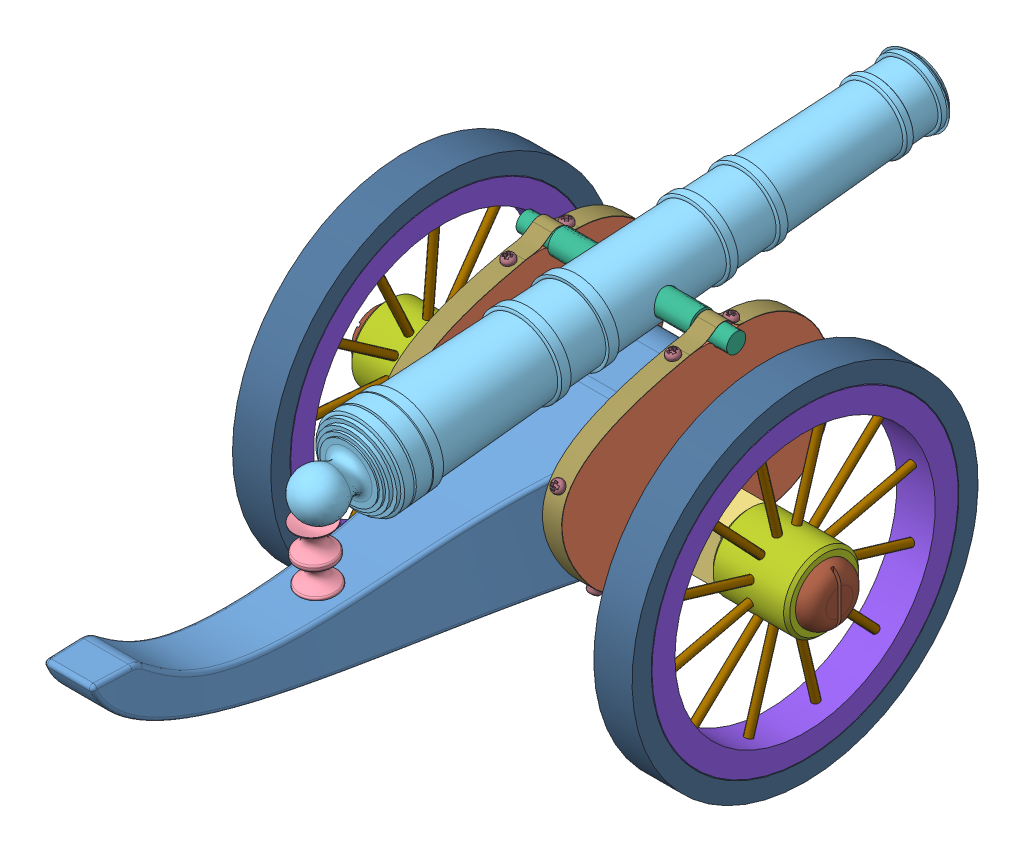
SolidWorks assembly ModelCannon, configuration Default. Lengths in mm.
Overall size (156.04 152.73 283.8).
65 component instances, 14 part files, 74 mates.
Components (placement in the parent):
- Body-1: Body [Default] at (64.8503 106.6025 167.4503) size (66.11 50.71 208.98)
- SideSupport-1: SideSupport [Default] at (37.5453 116.1275 93.9173) size (6.35 57.15 95.65)
- SideSupport-2: SideSupport [Default] at (92.1553 116.1275 93.9173) size (6.35 57.15 95.65)
- Axle-1: Axle [Default] at (64.8503 96.0615 93.7903) size (93.98 16.51 16.51)
- Bolster-1: Bolster [Default] at (64.8503 119.3352 189.7053) x (1 0 0) z (0 -0.083524 0.996506) size (12.7 31.75 12.7)
- Barrel-1: Barrel [Default] at (64.8503 144.7025 85.0053) x (1 0 0) z (0 0.086593 -0.996244) size (28.78 28.78 208.03)
- BarrelAxle-1: BarrelAxle [Default] at (64.8503 144.7025 85.0053) x (-1 0 0) z (0 0.924225 0.381849) size (69.85 8.13 8.13)
- Wheel-1: Wheel [Default] at (113.4219 81.2489 76.5414) x (1 0 0) z (0 0.203628 0.979048) size (25.4 129.14 129.14)
  - Hub-1: Hub [Default] at (11.6263 10.9898 19.9037) size (25.4 24.89 24.89)
  - InnerRim-1: InnerRim [Default] at (11.6263 10.9898 19.9037) x (1 0 0) z (0 -0.325508 0.945539) size (12.7 101.6 101.6)
  - Spoke-1: Spoke [Default] at (11.6263 -16.3912 7.1017) x (0.733186 -0.288022 0.616021) z (-0.680028 -0.310536 0.664175) size (2.54 40.64 2.54)
  - Spoke-2: Spoke [Default] at (11.6263 -19.1238 22.5073) x (0.45302 0.076792 0.888187) z (-0.8915 0.039022 0.451337) size (2.54 40.64 2.54)
  - Spoke-3: Spoke [Default] at (11.6263 -6.3218 -4.8737) x (-0.558086 -0.680204 0.47525) z (-0.829783 0.457484 -0.319638) size (2.54 40.64 2.54)
  - Spoke-4: Spoke [Default] at (11.6263 -13.7876 37.2153) x (1 0 0) z (0 0.572739 0.819737) size (2.54 40.64 2.54)
  - Spoke-5: Spoke [Default] at (11.6263 -1.8122 47.2847) x (0.999266 -0.0347 -0.016224) z (0.038306 0.905211 0.423233) size (2.54 40.64 2.54)
  - Spoke-6: Spoke [Default] at (11.6263 8.3862 -10.21) x (0.430926 -0.899033 0.07773) z (-0.902387 -0.429324 0.037119) size (2.54 40.64 2.54)
  - Spoke-7: Spoke [Default] at (11.6263 23.7918 -7.4773) x (1 0 0) z (0 0.905876 0.423544) size (2.54 40.64 2.54)
  - Spoke-8: Spoke [Default] at (11.6263 13.5934 50.0173) x (0.808821 -0.58587 0.050654) z (-0.588055 -0.805815 0.06967) size (2.54 40.64 2.54)
  - Spoke-9: Spoke [Default] at (11.6263 28.3014 44.6811) x (0.274974 0.788138 -0.550661) z (0.961452 -0.225406 0.157488) size (2.54 40.64 2.54)
  - Spoke-10: Spoke [Default] at (11.6263 41.1035 17.3001) x (0.021573 0.086118 0.996051) z (-0.999767 0.001858 0.021493) size (2.54 40.64 2.54)
  - Spoke-11: Spoke [Default] at (11.6263 35.7672 2.5921) x (0.597522 0.459253 0.657309) z (-0.801853 0.342224 0.489811) size (2.54 40.64 2.54)
  - Spoke-12: Spoke [Default] at (11.6263 38.3708 32.7057) x (0.995605 -0.039667 0.08484) z (-0.093656 -0.421682 0.901894) size (2.54 40.64 2.54)
  - OuterRim-1: OuterRim [Default] at (11.6263 10.9898 19.9037) size (12.7 114.81 114.81)
- Wheel-2: Wheel [Default] at (-6.4661 85.0716 73.8866) size (25.4 129.14 129.14)
  - Hub-1: Hub [Default] at (11.6263 10.9898 19.9037) size (25.4 24.89 24.89)
  - InnerRim-1: InnerRim [Default] at (11.6263 10.9898 19.9037) x (1 0 0) z (0 -0.325508 0.945539) size (12.7 101.6 101.6)
  - Spoke-1: Spoke [Default] at (11.6263 -16.3912 7.1017) x (0.733186 -0.288022 0.616021) z (-0.680028 -0.310536 0.664175) size (2.54 40.64 2.54)
  - Spoke-2: Spoke [Default] at (11.6263 -19.1238 22.5073) x (0.45302 0.076792 0.888187) z (-0.8915 0.039022 0.451337) size (2.54 40.64 2.54)
  - Spoke-3: Spoke [Default] at (11.6263 -6.3218 -4.8737) x (-0.558086 -0.680204 0.47525) z (-0.829783 0.457484 -0.319638) size (2.54 40.64 2.54)
  - Spoke-4: Spoke [Default] at (11.6263 -13.7876 37.2153) x (1 0 0) z (0 0.572739 0.819737) size (2.54 40.64 2.54)
  - Spoke-5: Spoke [Default] at (11.6263 -1.8122 47.2847) x (0.999266 -0.0347 -0.016224) z (0.038306 0.905211 0.423233) size (2.54 40.64 2.54)
  - Spoke-6: Spoke [Default] at (11.6263 8.3862 -10.21) x (0.430926 -0.899033 0.07773) z (-0.902387 -0.429324 0.037119) size (2.54 40.64 2.54)
  - Spoke-7: Spoke [Default] at (11.6263 23.7918 -7.4773) x (1 0 0) z (0 0.905876 0.423544) size (2.54 40.64 2.54)
  - Spoke-8: Spoke [Default] at (11.6263 13.5934 50.0173) x (0.808821 -0.58587 0.050654) z (-0.588055 -0.805815 0.06967) size (2.54 40.64 2.54)
  - Spoke-9: Spoke [Default] at (11.6263 28.3014 44.6811) x (0.274974 0.788138 -0.550661) z (0.961452 -0.225406 0.157488) size (2.54 40.64 2.54)
  - Spoke-10: Spoke [Default] at (11.6263 41.1035 17.3001) x (0.021573 0.086118 0.996051) z (-0.999767 0.001858 0.021493) size (2.54 40.64 2.54)
  - Spoke-11: Spoke [Default] at (11.6263 35.7672 2.5921) x (0.597522 0.459253 0.657309) z (-0.801853 0.342224 0.489811) size (2.54 40.64 2.54)
  - Spoke-12: Spoke [Default] at (11.6263 38.3708 32.7057) x (0.995605 -0.039667 0.08484) z (-0.093656 -0.421682 0.901894) size (2.54 40.64 2.54)
  - OuterRim-1: OuterRim [Default] at (11.6263 10.9898 19.9037) size (12.7 114.81 114.81)
- WheelScrew-1: WheelScrew [Default] at (124.7943 96.0615 93.7903) x (0 -1 0) z (0 0 1) size (19.05 49.06 19.05)
- WheelScrew-2: WheelScrew [Default] at (5.4143 96.0615 93.7903) x (0 -0.701868 -0.712307) z (0 0.712307 -0.701868) size (19.05 49.06 19.05)
- CopperStrip-1: CopperStrip [Default] at (37.5453 116.1275 93.9173) size (6.35 61.09 89.18)
- CopperStrip-2: CopperStrip [Default] at (92.1553 116.1275 93.9173) size (6.35 61.09 89.18)
- SmallScrew-2: SmallScrew [Default] at (92.1553 140.8063 97.588) x (-0.302476 -0.207362 0.930327) z (0.953157 -0.065804 0.295232) size (4.06 8.22 4.06)
- SmallScrew-3: SmallScrew [Default] at (37.5453 97.6029 56.9597) x (1 0 0) z (0 -0.770151 0.637861) size (4.06 8.22 4.06)
- SmallScrew-4: SmallScrew [Default] at (37.5453 118.2993 69.4106) x (1 0 0) z (0 -0.969773 -0.244009) size (4.06 8.22 4.06)
- SmallScrew-5: SmallScrew [Default] at (92.1553 123.601 133.4113) x (1 0 0) z (0 0.862464 -0.506118) size (4.06 8.22 4.06)
- SmallScrew-6: SmallScrew [Default] at (92.1553 92.9297 122.4523) x (1 0 0) z (0 0.51955 0.85444) size (4.06 8.22 4.06)
- SmallScrew-7: SmallScrew [Default] at (92.1553 97.6029 56.9597) x (0.807604 0.454178 -0.376163) z (0.589725 -0.621977 0.515139) size (4.06 8.22 4.06)
- SmallScrew-8: SmallScrew [Default] at (92.1553 141.6545 79.1094) x (0.084554 0 0.996419) z (0.996419 0 -0.084554) size (4.06 8.22 4.06)
- SmallScrew-9: SmallScrew [Default] at (92.1553 90.6005 82.9953) x (-0.417971 0 -0.90846) z (0.90846 0 -0.417971) size (4.06 8.22 4.06)
- SmallScrew-10: SmallScrew [Default] at (92.1553 122.3563 53.2869) x (-0.522268 0.827004 0.208086) z (0.852781 0.506482 0.127438) size (4.06 8.22 4.06)
- SmallScrew-11: SmallScrew [Default] at (37.5453 90.6005 104.8393) size (4.06 8.22 4.06)
- SmallScrew-12: SmallScrew [Default] at (37.5453 90.6005 82.9953) size (4.06 8.22 4.06)
- SmallScrew-13: SmallScrew [Default] at (92.1553 90.6005 104.8393) x (0.096077 0 0.995374) z (-0.995374 0 0.096077) size (4.06 8.22 4.06)
- SmallScrew-14: SmallScrew [Default] at (37.5453 141.6545 79.1094) x (-0.68281 0 0.730596) z (0.730596 0 0.68281) size (4.06 8.22 4.06)
- SmallScrew-15: SmallScrew [Default] at (37.5453 123.601 133.4113) x (0.9252 0.327288 -0.192062) z (-0.379481 0.797951 -0.468261) size (4.06 8.22 4.06)
- SmallScrew-16: SmallScrew [Default] at (37.5453 140.8063 97.588) x (0.878793 0.103817 -0.465773) z (-0.477202 0.191184 -0.857745) size (4.06 8.22 4.06)
- SmallScrew-17: SmallScrew [Default] at (37.5453 92.9297 122.4523) x (1 0 0) z (0 0.51955 0.85444) size (4.06 8.22 4.06)
- SmallScrew-19: SmallScrew [Default] at (37.5453 122.3563 53.2869) x (0.909668 -0.402781 -0.101346) z (-0.415335 -0.882172 -0.221967) size (4.06 8.22 4.06)
- BigScrew-1: BigScrew [Default] at (85.8053 107.4915 82.3603) x (0 0.752048 0.659108) z (0 0.659108 -0.752048) size (6.35 21.7 6.35)
- BigScrew-2: BigScrew [Default] at (85.8053 107.4915 105.4743) x (0 -0.455233 0.890372) z (0 0.890372 0.455233) size (6.35 21.7 6.35)
- BigScrew-3: BigScrew [Default] at (43.8953 107.4915 105.4743) x (0 0.044529 -0.999008) z (0 0.999008 0.044529) size (6.35 21.7 6.35)
- BigScrew-4: BigScrew [Default] at (43.8953 107.4915 82.3603) x (0 -0.996116 -0.088054) z (0 0.088054 -0.996116) size (6.35 21.7 6.35)
- BigScrew-5: BigScrew [Default] at (64.8503 97.3315 93.7903) x (-0.837169 0 -0.546944) z (-0.546944 0 0.837169) size (6.35 21.7 6.35)
Mates (geometry in assembly coordinates):
- Coincident1: coincident aligned: circle of Body-1; cylinder of SideSupport-2 through (88.9803 107.4915 82.3603) axis (1 0 0) radius 1.27
- Concentric1: concentric aligned: cylinder of Body-1 through (82.6303 107.4915 105.4743) axis (1 0 0) radius 1.27; cylinder of SideSupport-2 through (88.9803 107.4915 105.4743) axis (1 0 0) radius 1.27
- Coincident2: coincident anti-aligned: plane of Body-1 through (88.9803 96.6338 221.3715) normal (1 0 0); plane of SideSupport-2 through (88.9803 116.1275 93.9173) normal (-1 0 0)
- Concentric2: concentric anti-aligned: cylinder of Body-1 through (47.0703 107.4915 82.3603) axis (-1 0 0) radius 1.27; cylinder of SideSupport-1 through (34.3703 107.4915 82.3603) axis (1 0 0) radius 1.27
- Concentric3: concentric anti-aligned: cylinder of Body-1 through (47.0703 107.4915 105.4743) axis (-1 0 0) radius 1.27; cylinder of SideSupport-1 through (34.3703 107.4915 105.4743) axis (1 0 0) radius 1.27
- Coincident3: coincident anti-aligned: plane of Body-1 through (40.7203 96.6338 221.3715) normal (-1 0 0); plane of SideSupport-1 through (40.7203 116.1275 93.9173) normal (1 0 0)
- Concentric4: concentric anti-aligned: cylinder of Body-1 through (64.8503 104.3165 93.7903) axis (0 -1 0) radius 1.2637; cylinder of Axle-1 through (64.8503 87.8065 93.7903) axis (0 1 0) radius 1.27
- Coincident4: coincident anti-aligned: plane of Body-1 through (88.9803 104.3165 85.5353) normal (0 -1 0); plane of Axle-1 through (111.8403 104.3165 102.0453) normal (0 1 0)
- Concentric5: concentric aligned: cylinder of Body-1 through (64.8503 109.8435 188.9097) axis (0 0.996506 0.083524) radius 2.5527; cylinder of Bolster-1 through (64.8503 109.8435 188.9097) axis (0 0.996506 0.083524) radius 2.54
- Coincident5: coincident anti-aligned: circle of Body-1; plane of Bolster-1 through (64.8503 97.1878 187.849) normal (0 -0.996506 -0.083524)
- Coincident6: coincident anti-aligned: plane of Barrel-1; plane of BarrelAxle-1
- Concentric6: concentric aligned: cylinder of Barrel-1 through (52.1503 144.7025 85.0053) axis (1 0 0) radius 4.191; cylinder of BarrelAxle-1 through (41.3553 144.7025 85.0053) axis (1 0 0) radius 4.064
- Coincident7: coincident aligned: plane of Body-1 through (64.8503 106.6025 167.4503) normal (1 0 0); plane of Barrel-1
- Concentric8: concentric aligned: cylinder of SideSupport-2 through (88.9803 144.7025 85.0053) axis (1 0 0) radius 3.302; cylinder of BarrelAxle-1 through (29.9253 144.7025 85.0053) axis (1 0 0) radius 3.175
- Concentric9: concentric anti-aligned: cylinder of Wheel-1/Hub-1 through (103.368 96.0615 93.7903) axis (1 0 0) radius 3.175; cylinder of WheelScrew-1 through (137.7483 96.0615 93.7903) axis (-1 0 0) radius 3.048
- Concentric10: concentric aligned: cylinder of Wheel-1/OuterRim-1 through (131.3983 96.0615 93.7903) axis (-1 0 0) radius 57.404; cylinder of WheelScrew-1 through (137.7483 96.0615 93.7903) axis (-1 0 0) radius 3.048
- Concentric11: concentric anti-aligned: cylinder of Axle-1 through (94.0603 96.0615 93.7903) axis (1 0 0) radius 3.048; cylinder of WheelScrew-1 through (137.7483 96.0615 93.7903) axis (-1 0 0) radius 3.048
- Coincident11: coincident aligned: plane of Axle-1 through (111.8403 96.0615 93.7903) normal (1 0 0); circle of WheelScrew-1
- Parallel1: parallel anti-aligned: plane of Body-1 through (88.9803 87.5525 102.2993) normal (0 0 -1); plane of Axle-1 through (111.8403 104.3165 102.0453) normal (0 0 1)
- Coincident13: coincident anti-aligned: plane of Wheel-1/Hub-1 through (137.7483 96.0615 93.7903) normal (1 0 0); plane of WheelScrew-1 through (137.7483 96.0615 93.7903) normal (-1 0 0)
- Concentric12: concentric anti-aligned: cylinder of Axle-1 through (35.6403 96.0615 93.7903) axis (-1 0 0) radius 3.048; cylinder of WheelScrew-2 through (-7.5397 96.0615 93.7903) axis (1 0 0) radius 3.048
- Concentric14: concentric aligned: cylinder of Wheel-2/Hub-1 through (-16.52 96.0615 93.7903) axis (1 0 0) radius 3.175; cylinder of WheelScrew-2 through (-7.5397 96.0615 93.7903) axis (1 0 0) radius 3.048
- Coincident14: coincident anti-aligned: plane of Wheel-2/Hub-1 through (-7.5397 96.0615 93.7903) normal (-1 0 0); plane of WheelScrew-2 through (-7.5397 96.0615 93.7903) normal (1 0 0)
- Coincident15: coincident anti-aligned: plane of Axle-1 through (17.8603 96.0615 93.7903) normal (-1 0 0); plane of Wheel-2/Hub-1 through (17.8603 96.0615 93.7903) normal (1 0 0)
- Tangent1: tangent: circle of Bolster-1; sphere of Barrel-1
- Coincident19: coincident anti-aligned: plane of SideSupport-2 through (95.3303 87.5525 93.9173) normal (0 -1 0); plane of CopperStrip-2 through (95.3303 87.5525 71.8515) normal (0 1 0)
- Coincident20: coincident anti-aligned: plane of SideSupport-2 through (95.3303 116.1275 49.4673) normal (0 0 -1); plane of CopperStrip-2 through (95.3303 109.9367 49.4673) normal (0 0 1)
- Coincident21: coincident aligned: plane of SideSupport-2 through (92.1553 116.1275 93.9173) normal (1 0 0); plane of CopperStrip-2 through (92.1553 116.1275 93.9173) normal (1 0 0)
- Coincident22: coincident aligned: plane of SideSupport-1 through (37.5453 116.1275 93.9173) normal (1 0 0); plane of CopperStrip-1 through (37.5453 116.1275 93.9173) normal (1 0 0)
- Coincident23: coincident anti-aligned: plane of SideSupport-1 through (40.7203 87.5525 93.9173) normal (0 -1 0); plane of CopperStrip-1 through (40.7203 87.5525 71.8515) normal (0 1 0)
- Coincident24: coincident anti-aligned: plane of SideSupport-1 through (40.7203 116.1275 49.4673) normal (0 0 -1); plane of CopperStrip-1 through (40.7203 109.9367 49.4673) normal (0 0 1)
- Concentric15: concentric aligned: cylinder of SideSupport-2 through (92.1553 143.7811 98.2511) axis (0 0.976049 0.217553) radius 0.5954; cylinder of SmallScrew-2 through (92.1553 137.7073 96.8973) axis (0 0.976049 0.217553) radius 0.5953
- Concentric16: concentric aligned: cylinder of SideSupport-2 through (92.1553 144.7025 79.1094) axis (0 1 0) radius 0.5954; cylinder of SmallScrew-8 through (92.1553 138.4795 79.1094) axis (0 1 0) radius 0.5953
- Concentric17: concentric aligned: cylinder of SideSupport-2 through (92.1553 123.1 50.331) axis (0 0.244009 -0.969773) radius 0.5954; cylinder of SmallScrew-10 through (92.1553 121.5815 56.3659) axis (0 0.244009 -0.969773) radius 0.5953
- Concentric18: concentric aligned: cylinder of SideSupport-2 through (92.1553 95.6587 54.6123) axis (0 -0.637861 -0.770151) radius 0.5954; cylinder of SmallScrew-7 through (92.1553 99.6281 59.4049) axis (0 -0.637861 -0.770151) radius 0.5953
- Concentric19: concentric aligned: cylinder of SideSupport-2 through (92.1553 87.5525 82.9953) axis (0 -1 0) radius 0.5954; cylinder of SmallScrew-9 through (92.1553 93.7755 82.9953) axis (0 -1 0) radius 0.5953
- Concentric20: concentric aligned: cylinder of SideSupport-2 through (92.1553 87.5525 104.8393) axis (0 -1 0) radius 0.5954; cylinder of SmallScrew-13 through (92.1553 93.7755 104.8393) axis (0 -1 0) radius 0.5953
- Concentric21: concentric aligned: cylinder of SideSupport-2 through (92.1553 90.3254 124.0359) axis (0 -0.85444 0.51955) radius 0.5954; cylinder of SmallScrew-6 through (92.1553 95.6425 120.8027) axis (0 -0.85444 0.51955) radius 0.5953
- Concentric22: concentric aligned: cylinder of SideSupport-2 through (92.1553 125.1436 136.0401) axis (0 0.506118 0.862464) radius 0.5954; cylinder of SmallScrew-5 through (92.1553 121.994 130.673) axis (0 0.506118 0.862464) radius 0.5953
- Tangent2: tangent: face of CopperStrip-2; plane of SmallScrew-5 through (92.1553 125.2079 136.1497) normal (0 -0.506118 -0.862464)
- Tangent3: tangent: face of CopperStrip-2; plane of SmallScrew-2 through (92.1553 143.9052 98.2788) normal (0 -0.976049 -0.217553)
- Tangent5: tangent anti-aligned: cylinder of CopperStrip-2 through (92.1553 116.1275 78.0423) axis (1 0 0) radius 28.702; plane of SmallScrew-10 through (92.1553 123.131 50.2079) normal (0 -0.244009 0.969773)
- Coincident25: coincident anti-aligned: plane of CopperStrip-2 through (95.3303 87.4255 71.8515) normal (0 -1 0); plane of SmallScrew-9 through (92.1553 87.4255 82.9953) normal (0 1 0)
- Coincident26: coincident anti-aligned: plane of CopperStrip-2 through (95.3303 87.4255 114.1385) normal (0 -1 0); plane of SmallScrew-13 through (92.1553 87.4255 104.8393) normal (0 1 0)
- Tangent6: tangent anti-aligned: cylinder of CopperStrip-2 through (92.1553 106.6025 114.1385) axis (1 0 0) radius 19.177; plane of SmallScrew-6 through (92.1553 90.2168 124.1019) normal (0 0.85444 -0.51955)
- Tangent7: tangent: face of CopperStrip-2; circle of SmallScrew-8
- Concentric23: concentric aligned: cylinder of SideSupport-1 through (37.5453 123.1 50.331) axis (0 0.244009 -0.969773) radius 0.5954; cylinder of SmallScrew-4 through (37.5453 117.5246 72.4896) axis (0 0.244009 -0.969773) radius 0.5953
- Concentric24: concentric aligned: cylinder of SideSupport-1 through (37.5453 144.7025 79.1094) axis (0 1 0) radius 0.5954; cylinder of SmallScrew-14 through (37.5453 138.4795 79.1094) axis (0 1 0) radius 0.5953
- Concentric25: concentric aligned: cylinder of SideSupport-1 through (37.5453 143.7811 98.2511) axis (0 0.976049 0.217553) radius 0.5954; cylinder of SmallScrew-16 through (37.5453 137.7073 96.8973) axis (0 0.976049 0.217553) radius 0.5953
- Concentric26: concentric aligned: cylinder of SideSupport-1 through (37.5453 125.1436 136.0401) axis (0 0.506118 0.862464) radius 0.5954; cylinder of SmallScrew-15 through (37.5453 121.994 130.673) axis (0 0.506118 0.862464) radius 0.5953
- Concentric27: concentric aligned: cylinder of SideSupport-1 through (37.5453 90.3254 124.0359) axis (0 -0.85444 0.51955) radius 0.5954; cylinder of SmallScrew-17 through (37.5453 95.6425 120.8027) axis (0 -0.85444 0.51955) radius 0.5953
- Concentric28: concentric aligned: cylinder of SideSupport-1 through (37.5453 87.5525 104.8393) axis (0 -1 0) radius 0.5954; cylinder of SmallScrew-11 through (37.5453 93.7755 104.8393) axis (0 -1 0) radius 0.5953
- Concentric29: concentric aligned: cylinder of SideSupport-1 through (37.5453 87.5525 82.9953) axis (0 -1 0) radius 0.5954; cylinder of SmallScrew-12 through (37.5453 93.7755 82.9953) axis (0 -1 0) radius 0.5953
- Concentric30: concentric aligned: cylinder of SideSupport-1 through (37.5453 95.6587 54.6123) axis (0 -0.637861 -0.770151) radius 0.5954; cylinder of SmallScrew-3 through (37.5453 99.6281 59.4049) axis (0 -0.637861 -0.770151) radius 0.5953
- Tangent9: tangent anti-aligned: cylinder of CopperStrip-2 through (92.1553 109.9367 71.8515) axis (1 0 0) radius 22.5112; plane of SmallScrew-7 through (92.1553 95.5776 54.5145) normal (0 0.637861 0.770151)
- Concentric32: concentric aligned: cylinder of SideSupport-1 through (37.5453 123.1 50.331) axis (0 0.244009 -0.969773) radius 0.5954; cylinder of SmallScrew-19 through (37.5453 121.5815 56.3659) axis (0 0.244009 -0.969773) radius 0.5953
- Tangent10: tangent anti-aligned: cylinder of CopperStrip-1 through (37.5453 116.1275 78.0423) axis (1 0 0) radius 28.702; plane of SmallScrew-19 through (37.5453 123.131 50.2079) normal (0 -0.244009 0.969773)
- Tangent11: tangent: face of CopperStrip-1; plane of SmallScrew-14 through (37.5453 144.8295 79.1094) normal (0 -1 0)
- Tangent12: tangent: face of CopperStrip-1; plane of SmallScrew-16 through (37.5453 143.9052 98.2788) normal (0 -0.976049 -0.217553)
- Tangent13: tangent: face of CopperStrip-1; plane of SmallScrew-15 through (37.5453 125.2079 136.1497) normal (0 -0.506118 -0.862464)
- Tangent14: tangent anti-aligned: cylinder of CopperStrip-1 through (37.5453 106.6025 114.1385) axis (1 0 0) radius 19.177; plane of SmallScrew-17 through (37.5453 90.2168 124.1019) normal (0 0.85444 -0.51955)
- Coincident27: coincident anti-aligned: plane of CopperStrip-1 through (40.7203 87.4255 114.1385) normal (0 -1 0); plane of SmallScrew-11 through (37.5453 87.4255 104.8393) normal (0 1 0)
- Coincident28: coincident anti-aligned: plane of CopperStrip-1 through (40.7203 87.4255 71.8515) normal (0 -1 0); plane of SmallScrew-12 through (37.5453 87.4255 82.9953) normal (0 1 0)
- Tangent15: tangent anti-aligned: cylinder of CopperStrip-1 through (37.5453 109.9367 71.8515) axis (1 0 0) radius 22.5112; plane of SmallScrew-3 through (37.5453 95.5776 54.5145) normal (0 0.637861 0.770151)
- Concentric33: concentric anti-aligned: cylinder of SideSupport-2 through (88.9803 107.4915 105.4743) axis (1 0 0) radius 1.27; cylinder of BigScrew-2 through (95.3303 107.4915 105.4743) axis (-1 0 0) radius 1.27
- Concentric34: concentric anti-aligned: cylinder of SideSupport-2 through (88.9803 107.4915 82.3603) axis (1 0 0) radius 1.27; cylinder of BigScrew-1 through (95.3303 107.4915 82.3603) axis (-1 0 0) radius 1.27
- Concentric35: concentric aligned: cylinder of SideSupport-1 through (34.3703 107.4915 105.4743) axis (1 0 0) radius 1.27; cylinder of BigScrew-3 through (34.3703 107.4915 105.4743) axis (1 0 0) radius 1.27
- Concentric36: concentric aligned: cylinder of SideSupport-1 through (34.3703 107.4915 82.3603) axis (1 0 0) radius 1.27; cylinder of BigScrew-4 through (34.3703 107.4915 82.3603) axis (1 0 0) radius 1.27
- Concentric37: concentric aligned: cylinder of Axle-1 through (64.8503 87.8065 93.7903) axis (0 1 0) radius 1.27; cylinder of BigScrew-5 through (64.8503 87.8065 93.7903) axis (0 1 0) radius 1.27
- Coincident29: coincident anti-aligned: plane of Axle-1 through (111.8403 87.8065 102.0453) normal (0 -1 0); plane of BigScrew-5 through (64.8503 87.8065 93.7903) normal (0 1 0)
- Coincident30: coincident anti-aligned: plane of SideSupport-2 through (95.3303 116.1275 93.9173) normal (1 0 0); plane of BigScrew-1 through (95.3303 107.4915 82.3603) normal (-1 0 0)
- Coincident31: coincident anti-aligned: plane of SideSupport-2 through (95.3303 116.1275 93.9173) normal (1 0 0); plane of BigScrew-2 through (95.3303 107.4915 105.4743) normal (-1 0 0)
- Coincident32: coincident anti-aligned: plane of SideSupport-1 through (34.3703 116.1275 93.9173) normal (-1 0 0); plane of BigScrew-3 through (34.3703 107.4915 105.4743) normal (1 0 0)
- Coincident33: coincident anti-aligned: plane of SideSupport-1 through (34.3703 116.1275 93.9173) normal (-1 0 0); plane of BigScrew-4 through (34.3703 107.4915 82.3603) normal (1 0 0)
